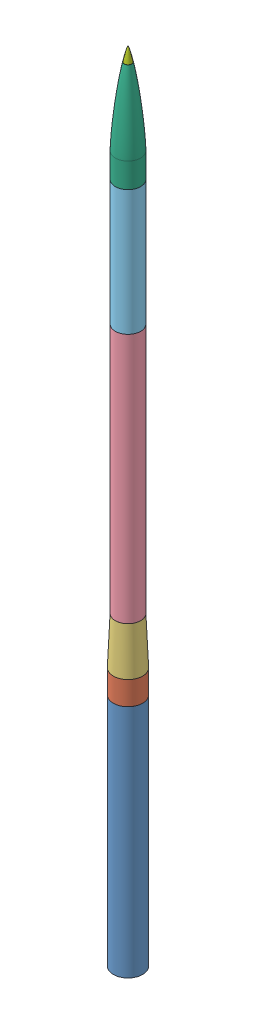
SolidWorks assembly Skipper_2, configuration Default. Lengths in mm.
Overall size (94.9 2584.26 94.9).
10 component instances, 7 part files, 16 mates.
Components (placement in the parent):
- S2_B_Airframe-1: S2_B_Airframe [Default] at origin size (94.9 838.2 94.9)
  - S2_B_Aft_Airframe-1: S2_B_Aft_Airframe [Default] at origin size (94.9 762 94.9)
  - S2_B_Forward_Airframe-1: S2_B_Forward_Airframe [Default] at (0 762 0) size (94.9 76.2 94.9)
- S2_C_Coupler-1: S2_C_Coupler [Default] at (0 838.2 0) size (94.9 152.4 94.9)
- S2_S_Airframe-1: S2_S_Airframe [Default] at (0 990.6 0) size (82.2 1219.2 82.2)
  - S2_S_Aft_Airframe-1: S2_S_Aft_Airframe [Default] at origin size (82.2 812.8 82.2)
  - S2_S_Forward_Airframe-2: S2_S_Forward_Airframe [Default] at (0 812.8 0) size (82.2 406.4 82.2)
- S2_Nose_Cone-1: S2_Nose_Cone [Default] at (0 2584.2614 0) size (82.2 374.46 82.2)
  - S2_NC_Nose_Cone-1: S2_NC_Nose_Cone [Default] x (0 -1 0) z (0 0 1) size (330.2 82.2 82.2)
  - S2_NC_Nose_Cone_Tip-1: S2_NC_Nose_Cone_Tip [Default] x (0 -1 0) z (0 0 1) size (44.45 24.48 24.48)
Mates (geometry in assembly coordinates):
- Coincident1: coincident aligned: line of S2_B_Airframe-1 through (110 0 -55) axis (0 0 1)
- Coincident2: coincident aligned: plane of S2_B_Airframe-1 through (0 0 0) normal (0 0 1)
- Coincident3: coincident aligned: plane of S2_B_Airframe-1 through (0 0 0) normal (0 1 0)
- Parallel1: parallel aligned: plane of S2_C_Coupler-1 through (0 838.2 0) normal (0 0 1)
- Coincident5: coincident aligned: line of S2_C_Coupler-1 through (167.64 0 830.58) axis (0 0 1)
- Parallel2: parallel aligned: plane of S2_S_Airframe-1 through (0 990.6 0) normal (0 0 1)
- Coincident7: coincident aligned: line of S2_S_Airframe-1 through (110 0 935.6) axis (0 0 1)
- Coincident8: coincident aligned: plane of S2_C_Coupler-1 through (0 990.6 0) normal (0 1 0); plane of S2_S_Airframe-1 through (0 990.6 0) normal (0 1 0)
- Coincident9: coincident aligned: plane of S2_B_Airframe-1/S2_B_Forward_Airframe-1 through (0 838.2 0) normal (0 1 0); plane of S2_C_Coupler-1 through (0 838.2 0) normal (0 1 0)
- Coincident10: coincident anti-aligned: line of S2_NC_Nose_Cone-1 through (0 2224.6945 0) axis (0 -1 0)
- Coincident11: coincident aligned: plane of S2_NC_Nose_Cone-2 through (0 2584.2614 0) normal (0 0 1)
- Coincident12: coincident anti-aligned: line of S2_NC_Nose_Cone-2 through (363.22 0 2556.3044) axis (0 0 -1)
- Coincident14: coincident anti-aligned: plane of S2_S_Airframe-1/S2_S_Forward_Airframe-2 through (0 2209.8 0) normal (0 1 0); plane of S2_NC_Nose_Cone-2 through (0 2209.8 0) normal (0 -1 0)
- Coincident15: coincident anti-aligned: line of S2_Nose_Cone-1 through (110 0 3746.9965) axis (0 0 -1)
- Parallel4: parallel aligned: plane of S2_Nose_Cone-1 through (0 3691.9965 0) normal (0 0 1)
- Coincident16: coincident anti-aligned: plane of S2_S_Airframe-1/S2_S_Forward_Airframe-2 through (0 2209.8 0) normal (0 1 0); plane of S2_Nose_Cone-1/S2_NC_Nose_Cone-1 through (0 3317.5352 0) normal (0 -1 0)
